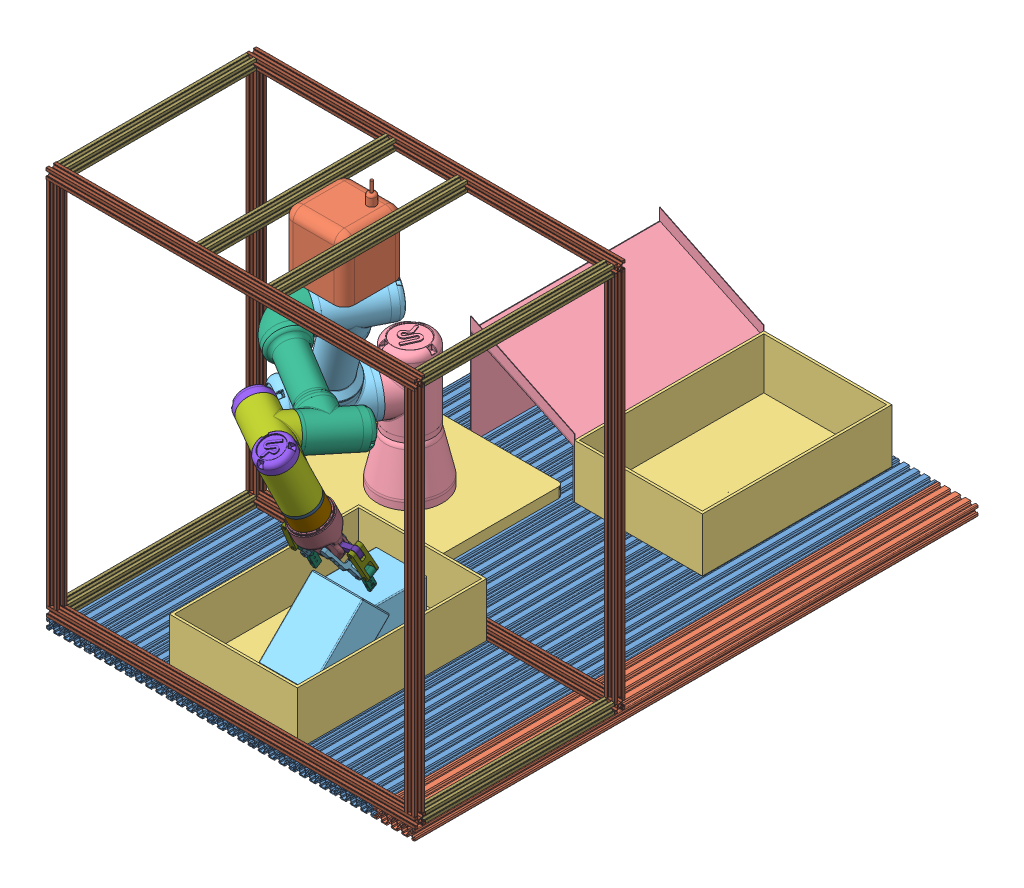
SolidWorks assembly Werkende opstelling, configuration Default. Lengths in mm.
Overall size (733.34 820 1100).
46 component instances, 23 part files, 84 mates.
Components (placement in the parent):
- V-Slot 20 x 80mm x 500mm-2: V-Slot 20 x 80mm x 500mm [Default] at (828.7682 821.7418 461.9753) size (320 20 1100)
- V-Slot 20 x 80mm x 500mm-4: V-Slot 20 x 80mm x 500mm [Default] at (1148.7636 821.7418 461.9753) size (320 20 1100)
- enkel v slot-1: enkel v slot [Default] at (1228.7636 821.7418 461.9753) size (80 20 1100)
- baseplate-1: baseplate [Default] at (728.7715 831.7418 1001.9753) size (300 30 300)
- Base^UR3 Assembly-1: Base^UR3 Assembly [Default] at (664.949 842.2242 909.9432) x (0.984522 0 -0.175261) z (0.175261 0 0.984522) size (131.37 250.8 133.51)
- Arm1^UR3 Assembly-1: Arm1^UR3 Assembly [Default] at (595.6225 918.2034 873.1559) x (0.887505 -0.401151 -0.226741) z (0.099337 -0.313933 0.944234) size (166.12 336.5 176.79)
- Arm2^UR3 Assembly-1: Arm2^UR3 Assembly [Default] at (503.2555 1468.7003 827.8955) x (0.046508 -0.745671 -0.664689) z (-0.545613 -0.576344 0.608386) size (139.42 296.06 133.37)
- size 0 shoulder 3-1: size 0 shoulder 3 [Default] at (839.9704 1229.95 1408.3477) x (0.422157 -0.168737 -0.89068) z (-0.203097 -0.975153 0.088477) size (73 98 65)
- Size 0 Cap-1: Size 0 Cap [Default] at (833.786 1230.9548 1405.2262) x (-0.174603 -0.984209 0.029109) z (0.434717 -0.103579 -0.894591) size (65 23.19 65.09)
- Tool holder-1: Tool holder [Default] at (959.4796 1163.0048 1444.9148) x (0.559094 -0.31368 0.767476) z (0.826718 0.2811 -0.487361) size (65 35 65)
- size 0 shoulder 3-2: size 0 shoulder 3 [Default] at (958.8509 1172.0745 1449.0796) x (-0.883479 0.143543 -0.445937) z (0.464234 0.395989 -0.792262) size (73 98 65)
- size 0  flange-1: size 0  flange [Default] at (917.7165 1217.3182 1447.5902) x (-0.025995 -0.965455 -0.25927) z (-0.467749 -0.217468 0.856691) size (65 6 65)
- Size 0 Cap-2: Size 0 Cap [Default] at (953.3191 1251.8875 1485.7303) x (0.574008 -0.308525 0.758503) z (-0.816433 -0.286747 0.501211) size (65 23.19 65.09)
- size 0  flange-2: size 0  flange [Default] at (959.6682 1160.2839 1443.6653) x (0.87749 0.249034 -0.40987) z (0.475458 -0.339697 0.811509) size (65 6 65)
- alüminyum profil (20x20)-1: alüminyum profil (20x20) [Varsayılan] at (588.7715 1571.7418 1551.9753) x (-1 0 0) z (0 0 1) size (20 720 20)
- alüminyum profil (20x20)-2: alüminyum profil (20x20) [Varsayılan] at (1288.7625 1571.7418 1161.9753) x (-1 0 0) z (0 0 1) size (20 720 20)
- alüminyum profil (20x20)-3: alüminyum profil (20x20) [Varsayılan] at (588.7715 1571.7418 1161.9753) x (-1 0 0) z (0 0 1) size (20 720 20)
- alüminyum profil (20x20)-4: alüminyum profil (20x20) [Varsayılan] at (1287.7265 1571.7418 1551.9753) x (-1 0 0) z (0 0 1) size (20 720 20)
- alüminyum profil (20x20)-5: alüminyum profil (20x20) [Varsayılan] at (1297.7265 1581.7418 1551.9753) x (0 1 0) z (0 0 1) size (20 720 20)
- alüminyum profil (20x20)-6: alüminyum profil (20x20) [Varsayılan] at (1298.7625 1581.7418 1161.9753) x (0 1 0) z (0 0 1) size (20 720 20)
- alüminyum profil (20x20) - Copy-1: alüminyum profil (20x20) - Copy [Varsayılan] at (1287.7265 1581.7418 1541.9753) x (0 1 0) z (-1 0 0) size (20 370 20)
- alüminyum profil (20x20) - Copy-2: alüminyum profil (20x20) - Copy [Varsayılan] at (588.7625 1581.7418 1541.9753) x (0 1 0) z (-1 0 0) size (20 370 20)
- alüminyum profil (20x20) - Copy-3: alüminyum profil (20x20) - Copy [Varsayılan] at (1288.351 841.7418 1541.9753) x (0 1 0) z (-1 0 0) size (20 370 20)
- alüminyum profil (20x20) - Copy-4: alüminyum profil (20x20) - Copy [Varsayılan] at (588.7715 841.7418 1541.9753) x (0 1 0) z (-1 0 0) size (20 370 20)
- alüminyum profil (20x20) - Copy-5: alüminyum profil (20x20) - Copy [Varsayılan] at (861.4217 1581.7418 1541.9753) x (0 1 0) z (-1 0 0) size (20 370 20)
- alüminyum profil (20x20) - Copy-6: alüminyum profil (20x20) - Copy [Varsayılan] at (1001.4217 1581.7418 1541.9753) x (0 1 0) z (-1 0 0) size (20 370 20)
- alüminyum profil (20x20)-7: alüminyum profil (20x20) [Varsayılan] at (1298.7625 841.7418 1551.9753) x (0 1 0) z (0 0 1) size (20 720 20)
- alüminyum profil (20x20)-8: alüminyum profil (20x20) [Varsayılan] at (1298.7715 841.7418 1161.9753) x (0 1 0) z (0 0 1) size (20 720 20)
- 2-Finger_85_Adaptive_Gripper-opened-1: 2-Finger_85_Adaptive_Gripper-opened [Default] at (967.3303 1049.736 1392.9009) x (-0.994944 -0.089699 0.045163) z (0.078319 -0.411541 0.90802) size (155.27 146.85 75)
  - Group1^2-Finger_85_Adaptive_Gripper-1: Group1^2-Finger_85_Adaptive_Gripper [Default] at origin size (89.6 94.04 75)
  - Group2^2-Finger_85_Adaptive_Gripper-1: Group2^2-Finger_85_Adaptive_Gripper [Default] at (-12.7 -28.58 0) x (0.759872 0.650073 0) z (0 0 1) size (12 69.15 39)
  - Group2^2-Finger_85_Adaptive_Gripper-2: Group2^2-Finger_85_Adaptive_Gripper [Default] at (12.7 -28.58 0) x (0.759872 -0.650073 0) z (0 0 1) size (12 69.15 39)
  - Group3^2-Finger_85_Adaptive_Gripper-1: Group3^2-Finger_85_Adaptive_Gripper [Default] at (0.4488 0.3881 0) x (1 0 0) z (0 0 1) size (29.9 50.51 15)
  - Group3^2-Finger_85_Adaptive_Gripper-2: Group3^2-Finger_85_Adaptive_Gripper [Default] at (-0.4488 0.3881 0) x (-1 0 0) z (0 0 -1) size (29.9 50.51 15)
  - Group4^2-Finger_85_Adaptive_Gripper-1: Group4^2-Finger_85_Adaptive_Gripper [Default] at (0.3627 -0.3196 0) x (0.999946 -0.010382 0) z (0 0 1) size (18.11 59.12 27)
  - Group4^2-Finger_85_Adaptive_Gripper-2: Group4^2-Finger_85_Adaptive_Gripper [Default] at (131.9261 -16.0902 0) x (0.969481 -0.245165 0) z (0 0 1) size (18.11 59.12 27)
  - Group5^2-Finger_85_Adaptive_Gripper-1: Group5^2-Finger_85_Adaptive_Gripper [Default] at (-0.3627 -0.3196 0) x (0.999946 0.010382 0) z (0 0 1) size (46.27 22.95 24)
  - Group5^2-Finger_85_Adaptive_Gripper-2: Group5^2-Finger_85_Adaptive_Gripper [Default] at (0.3627 -0.3196 0) x (-0.999946 0.010382 0) z (0 0 -1) size (46.27 22.95 24)
  - Group6^2-Finger_85_Adaptive_Gripper-1: Group6^2-Finger_85_Adaptive_Gripper [Default] at (0 -4 0) x (1 0 0) z (0 1 0) size (31 20 4)
  - Group7^2-Finger_85_Adaptive_Gripper-1: Group7^2-Finger_85_Adaptive_Gripper [Default] at origin size (28.5 12 17.5)
- camera-1: camera [Default] at (877.4217 1471.7418 1286.5899) size (120 160 120)
- bak-1: bak [Default] at (923.7715 836.7418 1356.9753) x (0 0 1) z (-1 0 0) size (370 105 250)
- bak-2: bak [Default] at (1025.2865 836.7418 666.9753) x (0 0 1) z (-1 0 0) size (370 105 250)
- glijbaan-1: glijbaan [Default] at (797.2865 825.7418 666.9753) x (0 0 -1) z (1 0 0) size (370 219.47 203)
- blokje-1: blokje [Default] at (911.4185 836.7418 1274.7831) size (100 75 150)
- blokje-2: blokje [Default] at (963.4711 881.8034 1377.7216) x (1 0 0) z (0 -0.707107 0.707107) size (100 75 150)
Mates (geometry in assembly coordinates):
- Coincident4: coincident aligned: plane of V-Slot 20 x 80mm x 500mm-2 through (828.7682 831.7418 1561.9753) normal (0 1 0); plane of V-Slot 20 x 80mm x 500mm-4 through (968.7659 831.7418 1561.9753) normal (0 1 0)
- Coincident5: coincident anti-aligned: plane of V-Slot 20 x 80mm x 500mm-2 through (898.767 821.7418 1561.9753) normal (1 0 0); plane of V-Slot 20 x 80mm x 500mm-4 through (898.767 821.7418 1561.9753) normal (-1 0 0)
- Coincident6: coincident aligned: plane of V-Slot 20 x 80mm x 500mm-2 through (828.7682 821.7418 1561.9753) normal (0 0 1); plane of V-Slot 20 x 80mm x 500mm-4 through (1148.7636 821.7418 1561.9753) normal (0 0 1)
- Coincident8: coincident anti-aligned: plane of V-Slot 20 x 80mm x 500mm-4 through (1218.7625 821.7418 1561.9753) normal (1 0 0); plane of enkel v slot-1 through (1218.7625 821.7418 1561.9753) normal (-1 0 0)
- Coincident9: coincident aligned: plane of V-Slot 20 x 80mm x 500mm-4 through (1148.7636 831.7418 1561.9753) normal (0 1 0); plane of enkel v slot-1 through (1228.7636 831.7418 1561.9753) normal (0 1 0)
- Coincident10: coincident aligned: plane of V-Slot 20 x 80mm x 500mm-4 through (1148.7636 821.7418 1561.9753) normal (0 0 1); plane of enkel v slot-1 through (1228.7636 821.7418 1561.9753) normal (0 0 1)
- Distance1: distance = 410 mm aligned: plane of baseplate-1 through (578.7715 851.7418 1151.9753) normal (0 0 1); plane of V-Slot 20 x 80mm x 500mm-2 through (828.7682 821.7418 1561.9753) normal (0 0 1)
- Concentric1: concentric anti-aligned: cylinder of baseplate-1 through (728.7715 861.7418 1001.9753) axis (0 -1 0) radius 16.2225; cone of Base^UR3 Assembly-1 through (728.7715 851.7418 1001.9753) axis (0 1 0)
- Coincident12: coincident anti-aligned: plane of baseplate-1 through (728.7715 851.7418 1001.9753) normal (0 1 0); plane of Base^UR3 Assembly-1 through (728.7715 851.7418 1001.9753) normal (0 -1 0)
- Coincident15: coincident aligned: plane of V-Slot 20 x 80mm x 500mm-2 through (578.7715 821.7418 1561.9753) normal (-1 0 0); plane of baseplate-1 through (578.7715 851.7418 851.9753) normal (-1 0 0)
- Coincident16: coincident anti-aligned: plane of V-Slot 20 x 80mm x 500mm-2 through (648.7704 831.7418 1561.9753) normal (0 1 0); plane of baseplate-1 through (728.7715 831.7418 1001.9753) normal (0 -1 0)
- Parallel2: parallel aligned: cylinder of Base^UR3 Assembly-1 through (702.9911 1023.5418 1050.5589) axis (0.468735 0 -0.883339) radius 42.5; cylinder of Arm1^UR3 Assembly-1 through (695.7961 1023.5418 1064.1182) axis (0.468735 0 -0.883339) radius 42.5
- Coincident17: coincident anti-aligned: plane of Base^UR3 Assembly-1 through (705.3348 1023.5418 1046.1422) normal (-0.468735 0 0.883339); plane of Arm1^UR3 Assembly-1 through (705.3348 1023.5418 1046.1422) normal (0.468735 0 -0.883339)
- Concentric4: concentric aligned: cylinder of Base^UR3 Assembly-1 through (702.9911 1023.5418 1050.5589) axis (0.468735 0 -0.883339) radius 42.5; cylinder of Arm1^UR3 Assembly-1 through (695.7961 1023.5418 1064.1182) axis (0.468735 0 -0.883339) radius 42.5
- Concentric5: concentric anti-aligned: cylinder of Arm1^UR3 Assembly-1 through (743.2195 1254.9638 1203.2227) axis (-0.460489 -0.004284 0.887655) radius 35; cylinder of Arm2^UR3 Assembly-1 through (738.6146 1254.9209 1212.0992) axis (0.460489 0.004284 -0.887655) radius 35
- Coincident19: coincident anti-aligned: plane of Arm1^UR3 Assembly-1 through (738.6146 1254.9209 1212.0992) normal (-0.460489 -0.004284 0.887655); plane of Arm2^UR3 Assembly-1 through (738.6146 1254.9209 1212.0992) normal (0.460489 0.004284 -0.887655)
- Concentric7: concentric aligned: cylinder of Arm2^UR3 Assembly-1 through (896.3238 1216.4376 1388.7784) axis (-0.422157 0.168737 0.89068) radius 30; cylinder of size 0 shoulder 3-1 through (895.0573 1216.9438 1391.4505) axis (-0.422157 0.168737 0.89068) radius 30
- Coincident21: coincident anti-aligned: plane of Arm2^UR3 Assembly-1 through (893.7909 1217.45 1394.1225) normal (-0.422157 0.168737 0.89068); plane of size 0 shoulder 3-1 through (893.7909 1217.45 1394.1225) normal (0.422157 -0.168737 -0.89068)
- Concentric8: concentric aligned: cylinder of size 0 shoulder 3-1 through (917.7165 1217.3182 1447.5902) axis (-0.883479 0.143543 -0.445937) radius 32.5; cylinder of size 0  flange-1 through (923.0174 1216.4569 1450.2658) axis (-0.883479 0.143543 -0.445937) radius 30
- Concentric9: concentric aligned: cylinder of size 0 shoulder 3-1 through (917.7165 1217.3182 1447.5902) axis (-0.883479 0.143543 -0.445937) radius 32.5; cylinder of size 0  flange-1 through (923.0174 1216.4569 1450.2658) axis (-0.883479 0.143543 -0.445937) radius 32.5
- Coincident22: coincident anti-aligned: plane of size 0 shoulder 3-1 through (917.7165 1217.3182 1447.5902) normal (0.883479 -0.143543 0.445937); plane of size 0  flange-1 through (917.7165 1217.3182 1447.5902) normal (-0.883479 0.143543 -0.445937)
- Concentric12: concentric anti-aligned: cylinder of size 0 shoulder 3-2 through (920.367 1216.8875 1448.928) axis (0.883479 -0.143543 0.445937) radius 30; cylinder of size 0  flange-1 through (923.0174 1216.4569 1450.2658) axis (-0.883479 0.143543 -0.445937) radius 30
- Coincident24: coincident anti-aligned: plane of size 0 shoulder 3-2 through (923.0174 1216.4569 1450.2658) normal (-0.883479 0.143543 -0.445937); plane of size 0  flange-1 through (923.0174 1216.4569 1450.2658) normal (0.883479 -0.143543 0.445937)
- Concentric13: concentric aligned: cylinder of size 0 shoulder 3-1 through (831.1356 1231.3854 1403.8884) axis (0.883479 -0.143543 0.445937) radius 30; cylinder of Size 0 Cap-1 through (813.466 1234.2563 1394.9696) axis (0.883479 -0.143543 0.445937) radius 31.5
- Coincident25: coincident anti-aligned: plane of size 0 shoulder 3-1 through (833.786 1230.9548 1405.2262) normal (-0.883479 0.143543 -0.445937); plane of Size 0 Cap-1 through (833.786 1230.9548 1405.2262) normal (0.883479 -0.143543 0.445937)
- Concentric14: concentric aligned: cylinder of Tool holder-1 through (959.6682 1160.2839 1443.6653) axis (-0.062862 0.906966 0.416486) radius 30; cylinder of size 0 shoulder 3-2 through (959.4796 1163.0048 1444.9148) axis (-0.062862 0.906966 0.416486) radius 30
- Coincident26: coincident anti-aligned: plane of size 0 shoulder 3-2 through (953.3191 1251.8875 1485.7303) normal (-0.062862 0.906966 0.416486); plane of Size 0 Cap-2 through (953.3191 1251.8875 1485.7303) normal (0.062862 -0.906966 -0.416486)
- Concentric15: concentric aligned: circle of size 0 shoulder 3-2; circle of Size 0 Cap-2
- Coincident27: coincident anti-aligned: plane of size 0 shoulder 3-2 through (959.291 1165.7257 1446.1642) normal (0.062862 -0.906966 -0.416486); plane of size 0  flange-2 through (959.291 1165.7257 1446.1642) normal (-0.062862 0.906966 0.416486)
- Concentric16: concentric anti-aligned: cylinder of size 0 shoulder 3-2 through (959.4796 1163.0048 1444.9148) axis (-0.062862 0.906966 0.416486) radius 30; cylinder of size 0  flange-2 through (959.291 1165.7257 1446.1642) axis (0.062862 -0.906966 -0.416486) radius 30
- Coincident28: coincident anti-aligned: plane of Tool holder-1 through (959.6682 1160.2839 1443.6653) normal (-0.062862 0.906966 0.416486); plane of size 0  flange-2 through (959.6682 1160.2839 1443.6653) normal (0.062862 -0.906966 -0.416486)
- Coincident30: coincident aligned: plane of V-Slot 20 x 80mm x 500mm-2 through (828.7682 821.7418 1561.9753) normal (0 0 1); plane of alüminyum profil (20x20)-1 through (584.1215 851.7418 1561.9753) normal (0 0 1)
- Coincident31: coincident aligned: plane of V-Slot 20 x 80mm x 500mm-2 through (578.7715 821.7418 1561.9753) normal (-1 0 0); plane of alüminyum profil (20x20)-1 through (578.7715 851.7418 1547.3253) normal (-1 0 0)
- Coincident34: coincident aligned: plane of enkel v slot-1 through (1228.7636 821.7418 1561.9753) normal (0 0 1); plane of alüminyum profil (20x20)-4 through (1297.5265 851.7418 1561.9753) normal (0 0 1)
- Coincident37: coincident anti-aligned: plane of baseplate-1 through (578.7715 851.7418 1151.9753) normal (0 0 1); plane of alüminyum profil (20x20)-3 through (584.1215 851.7418 1151.9753) normal (0 0 -1)
- Coincident39: coincident aligned: plane of enkel v slot-1 through (1298.7625 821.7418 1561.9753) normal (1 0 0); plane of alüminyum profil (20x20)-2 through (1298.7625 851.7418 1157.3253) normal (1 0 0)
- Coincident40: coincident anti-aligned: plane of baseplate-1 through (578.7715 851.7418 1151.9753) normal (0 0 1); plane of alüminyum profil (20x20)-2 through (1298.5625 851.7418 1151.9753) normal (0 0 -1)
- Coincident41: coincident aligned: plane of alüminyum profil (20x20)-4 through (1297.7265 851.7418 1561.7753) normal (1 0 0); plane of alüminyum profil (20x20)-5 through (1297.7265 1571.9418 1542.1753) normal (1 0 0)
- Coincident43: coincident aligned: plane of alüminyum profil (20x20)-4 through (1297.5265 851.7418 1561.9753) normal (0 0 1); plane of alüminyum profil (20x20)-5 through (577.7265 1586.3918 1561.9753) normal (0 0 1)
- Coincident44: coincident aligned: plane of alüminyum profil (20x20)-2 through (1298.7625 851.7418 1171.7753) normal (1 0 0); plane of alüminyum profil (20x20)-6 through (1298.7625 1571.9418 1152.1753) normal (1 0 0)
- Coincident45: coincident anti-aligned: plane of alüminyum profil (20x20)-2 through (1298.5625 1571.7418 1152.1753) normal (0 1 0); plane of alüminyum profil (20x20)-6 through (578.7625 1571.7418 1171.7753) normal (0 -1 0)
- Coincident46: coincident aligned: plane of alüminyum profil (20x20)-2 through (1298.5625 851.7418 1171.9753) normal (0 0 1); plane of alüminyum profil (20x20)-6 through (578.7625 1571.9418 1171.9753) normal (0 0 1)
- Coincident47: coincident aligned: plane of alüminyum profil (20x20)-5 through (577.7265 1591.7418 1547.3253) normal (0 1 0); plane of alüminyum profil (20x20) - Copy-1 through (1277.9265 1591.7418 1171.9753) normal (0 1 0)
- Coincident48: coincident anti-aligned: plane of alüminyum profil (20x20)-5 through (577.7265 1586.3918 1541.9753) normal (0 0 -1); plane of alüminyum profil (20x20) - Copy-1 through (1297.5265 1571.9418 1541.9753) normal (0 0 1)
- Coincident49: coincident aligned: plane of alüminyum profil (20x20)-5 through (1297.7265 1571.9418 1542.1753) normal (1 0 0); plane of alüminyum profil (20x20) - Copy-1 through (1297.7265 1586.3918 1171.9753) normal (1 0 0)
- Coincident50: coincident anti-aligned: plane of alüminyum profil (20x20)-6 through (578.7625 1586.3918 1171.9753) normal (0 0 1); plane of alüminyum profil (20x20) - Copy-2 through (598.5625 1571.9418 1171.9753) normal (0 0 -1)
- Coincident51: coincident aligned: plane of alüminyum profil (20x20)-6 through (578.7625 1571.9418 1152.1753) normal (-1 0 0); plane of alüminyum profil (20x20) - Copy-2 through (578.7625 1586.3918 1171.9753) normal (-1 0 0)
- Coincident52: coincident aligned: plane of alüminyum profil (20x20)-6 through (578.7625 1591.7418 1171.7753) normal (0 1 0); plane of alüminyum profil (20x20) - Copy-2 through (578.9625 1591.7418 1171.9753) normal (0 1 0)
- Coincident53: coincident aligned: plane of alüminyum profil (20x20)-3 through (578.7715 851.7418 1171.7753) normal (-1 0 0); plane of alüminyum profil (20x20) - Copy-4 through (578.7715 846.3918 1171.9753) normal (-1 0 0)
- Coincident54: coincident anti-aligned: plane of V-Slot 20 x 80mm x 500mm-2 through (648.7704 831.7418 1561.9753) normal (0 1 0); plane of alüminyum profil (20x20) - Copy-4 through (578.9715 831.7418 1171.9753) normal (0 -1 0)
- Coincident55: coincident anti-aligned: plane of alüminyum profil (20x20)-3 through (584.1215 851.7418 1171.9753) normal (0 0 1); plane of alüminyum profil (20x20) - Copy-4 through (598.5715 831.9418 1171.9753) normal (0 0 -1)
- Coincident56: coincident anti-aligned: plane of alüminyum profil (20x20)-6 through (578.7625 1586.3918 1171.9753) normal (0 0 1); plane of alüminyum profil (20x20) - Copy-5 through (871.2217 1571.9418 1171.9753) normal (0 0 -1)
- Coincident57: coincident aligned: plane of alüminyum profil (20x20)-5 through (577.7265 1591.7418 1547.3253) normal (0 1 0); plane of alüminyum profil (20x20) - Copy-5 through (851.6217 1591.7418 1171.9753) normal (0 1 0)
- Coincident58: coincident aligned: plane of alüminyum profil (20x20)-6 through (578.7625 1591.7418 1157.3253) normal (0 1 0); plane of alüminyum profil (20x20) - Copy-6 through (1006.0717 1591.7418 1171.9753) normal (0 1 0)
- Coincident59: coincident anti-aligned: plane of alüminyum profil (20x20)-6 through (578.7625 1586.3918 1171.9753) normal (0 0 1); plane of alüminyum profil (20x20) - Copy-6 through (1011.2217 1571.9418 1171.9753) normal (0 0 -1)
- Coincident60: coincident anti-aligned: plane of alüminyum profil (20x20)-2 through (1284.1125 851.7418 1171.9753) normal (0 0 1); plane of alüminyum profil (20x20) - Copy-3 through (1298.151 831.9418 1171.9753) normal (0 0 -1)
- Coincident61: coincident anti-aligned: plane of enkel v slot-1 through (1228.7636 831.7418 1561.9753) normal (0 1 0); plane of alüminyum profil (20x20) - Copy-3 through (1293.001 831.7418 1171.9753) normal (0 -1 0)
- Coincident62: coincident anti-aligned: plane of V-Slot 20 x 80mm x 500mm-4 through (1128.7636 831.7418 1561.9753) normal (0 1 0); plane of alüminyum profil (20x20)-7 through (578.7625 831.7418 1561.7753) normal (0 -1 0)
- Coincident64: coincident: line of alüminyum profil (20x20)-4 through (1283.0765 851.7418 1561.9753) axis (0 1 0); plane of alüminyum profil (20x20)-7 through (578.7625 846.3918 1561.9753) normal (0 0 1)
- Coincident66: coincident anti-aligned: plane of V-Slot 20 x 80mm x 500mm-2 through (648.7704 831.7418 1561.9753) normal (0 1 0); plane of alüminyum profil (20x20)-8 through (578.7715 831.7418 1171.7753) normal (0 -1 0)
- Coincident68: coincident aligned: plane of V-Slot 20 x 80mm x 500mm-2 through (578.7715 821.7418 1561.9753) normal (-1 0 0); plane of alüminyum profil (20x20)-8 through (578.7715 831.9418 1152.1753) normal (-1 0 0)
- Coincident69: coincident anti-aligned: plane of baseplate-1 through (578.7715 851.7418 1151.9753) normal (0 0 1); plane of alüminyum profil (20x20)-8 through (578.7715 846.3918 1151.9753) normal (0 0 -1)
- Coincident70: coincident aligned: plane of enkel v slot-1 through (1298.7625 821.7418 1561.9753) normal (1 0 0); plane of alüminyum profil (20x20)-7 through (1298.7625 831.9418 1542.1753) normal (1 0 0)
- Coincident71: coincident anti-aligned: plane of alüminyum profil (20x20)-3 through (598.5715 851.7418 1152.1753) normal (0 -1 0); plane of alüminyum profil (20x20)-8 through (578.7715 851.7418 1157.3253) normal (0 1 0)
- Coincident72: coincident aligned: plane of baseplate-1 through (578.7715 851.7418 851.9753) normal (-1 0 0); plane of alüminyum profil (20x20)-3 through (578.7715 851.7418 1157.3253) normal (-1 0 0)
- Symmetric1: symmetric anti-aligned: plane of alüminyum profil (20x20)-2 through (1298.5625 851.7418 1152.1753) normal (0 -1 0); plane of alüminyum profil (20x20)-8 through (578.7715 851.7418 1171.7753) normal (0 1 0); plane of alüminyum profil (20x20)-2 through (1298.7625 851.7418 1171.7753) normal (1 0 0)
- Coincident73: coincident anti-aligned: plane of alüminyum profil (20x20)-4 through (1297.5265 851.7418 1542.1753) normal (0 -1 0); plane of alüminyum profil (20x20)-7 through (578.7625 851.7418 1561.7753) normal (0 1 0)
- Coincident75: coincident anti-aligned: plane of alüminyum profil (20x20)-4 through (1297.5265 1571.7418 1542.1753) normal (0 1 0); plane of alüminyum profil (20x20)-5 through (577.7265 1571.7418 1561.7753) normal (0 -1 0)
- Coincident76: coincident anti-aligned: plane of alüminyum profil (20x20)-1 through (598.5715 851.7418 1542.1753) normal (0 -1 0); plane of alüminyum profil (20x20)-7 through (578.7625 851.7418 1561.7753) normal (0 1 0)
- Concentric18: concentric aligned: cylinder of Tool holder-1 through (961.6797 1131.261 1430.3378) axis (-0.062862 0.906966 0.416486) radius 32.5; cylinder of 2-Finger_85_Adaptive_Gripper-opened-1/Group1^2-Finger_85_Adaptive_Gripper-1 through (966.2001 1066.042 1400.3887) axis (-0.062862 0.906966 0.416486) radius 37.5
- Coincident77: coincident anti-aligned: plane of Tool holder-1 through (961.6797 1131.261 1430.3378) normal (0.062862 -0.906966 -0.416486); plane of 2-Finger_85_Adaptive_Gripper-opened-1/Group1^2-Finger_85_Adaptive_Gripper-1 through (961.6797 1131.261 1430.3378) normal (-0.062862 0.906966 0.416486)
- Coincident78: coincident anti-aligned: plane of alüminyum profil (20x20) - Copy-6 through (991.4217 1586.3918 1171.9753) normal (-1 0 0); plane of camera-1 through (991.4217 1591.7418 1272.8739) normal (1 0 0)
- Coincident79: coincident aligned: plane of alüminyum profil (20x20) - Copy-6 through (991.6217 1591.7418 1171.9753) normal (0 1 0); plane of camera-1 through (877.4217 1591.7418 1286.5899) normal (0 1 0)
- Coincident80: coincident anti-aligned: plane of alüminyum profil (20x20)-7 through (578.7625 846.3918 1541.9753) normal (0 0 -1); plane of bak-1 through (1048.7715 936.7418 1541.9753) normal (0 0 1)
- Distance2: distance = 200 mm anti-aligned: plane of alüminyum profil (20x20) - Copy-4 through (598.7715 846.3918 1171.9753) normal (1 0 0); plane of bak-1 through (798.7715 936.7418 1171.9753) normal (-1 0 0)
- Coincident82: coincident anti-aligned: plane of alüminyum profil (20x20) - Copy-5 through (871.4217 1586.3918 1171.9753) normal (1 0 0); plane of camera-1 through (871.4217 1591.7418 1272.8739) normal (-1 0 0)
- Coincident83: coincident anti-aligned: plane of V-Slot 20 x 80mm x 500mm-4 through (988.7659 831.7418 1561.9753) normal (0 1 0); plane of bak-1 through (923.7715 831.7418 1356.9753) normal (0 -1 0)
- Coincident84: coincident anti-aligned: plane of baseplate-1 through (578.7715 851.7418 851.9753) normal (0 0 -1); plane of bak-2 through (1150.2865 936.7418 851.9753) normal (0 0 1)
- Coincident85: coincident anti-aligned: plane of V-Slot 20 x 80mm x 500mm-4 through (1148.7636 831.7418 1561.9753) normal (0 1 0); plane of bak-2 through (1025.2865 831.7418 666.9753) normal (0 -1 0)
- Coincident86: coincident anti-aligned: plane of bak-2 through (900.2865 936.7418 481.9753) normal (-1 0 0); plane of glijbaan-1 through (900.2865 825.7418 666.9753) normal (1 0 0)
- Coincident87: coincident anti-aligned: plane of V-Slot 20 x 80mm x 500mm-2 through (668.7704 825.7418 1561.9753) normal (0 1 0); plane of glijbaan-1 through (698.2865 825.7418 481.9753) normal (0 -1 0)
- Coincident88: coincident anti-aligned: plane of baseplate-1 through (578.7715 851.7418 851.9753) normal (0 0 -1); plane of glijbaan-1 through (797.2865 825.7418 851.9753) normal (0 0 1)
- Symmetric2: symmetric anti-aligned: plane of bak-1 through (923.7715 836.7418 1356.9753) normal (0 1 0); plane of blokje-1 through (911.4185 836.7418 1274.7831) normal (0 -1 0); plane of blokje-1 through (861.4185 911.7418 1349.7831) normal (0 0 1)
- Coincident89: coincident anti-aligned: plane of blokje-1 through (911.4185 911.7418 1347.7831) normal (0 0.707107 0.707107); plane of blokje-2 through (963.4711 881.8034 1377.7216) normal (0 -0.707107 -0.707107)
